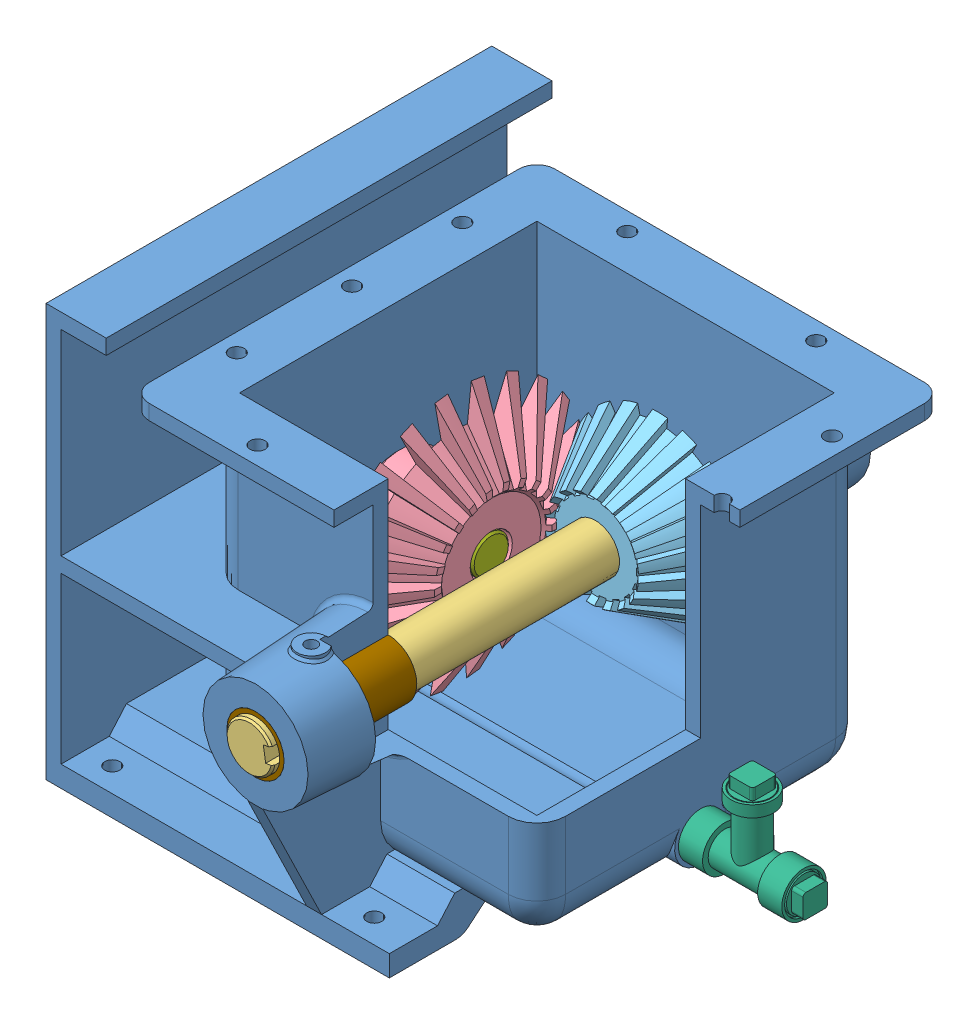
SolidWorks assembly Redutor do transportador helicoidal, configuration B. Lengths in mm.
Overall size (765.56 434.98 610).
10 component instances, 10 part files, 19 mates.
Components (placement in the parent):
- carcaça-1: carcaça [Valor predeterminado] at (-51.6856 -43.3778 0) size (496.49 434.98 593.28)
- peça 2-1: peça 2 [Valor predeterminado] at (-51.6856 -43.3778 -226.6406) x (0.95826 -0.2859 0) z (0 0 1) size (60 60 140)
- Peça 7-1: Peça 7 [Valor predeterminado] at (-47.7521 -42.7392 -61.7219) x (0 0 -1) z (0.160256 -0.987076 0) size (610 50.8 50.8)
- Peça 9B-1: Peça 9B [Valor predeterminado] at (-198.7206 -43.3778 0) x (1 0 0) z (0 0.964545 0.263918) size (104.77 270 268.87)
- Peça 9A-1: Peça 9A [Valor predeterminado] at (-51.6856 -43.3778 -153.7656) x (0 0 1) z (-0.662671 -0.74891 0) size (96.04 182.18 182.88)
- peça 21-1: peça 21 [Valor predeterminado] at (102.9549 -187.4434 0) size (138.87 105.45 46.9)
- Peça 4-1: Peça 4 [Valor predeterminado] at (-334.8151 -40.7927 0) size (423.91 48 48)
- Peça 5-1: Peça 5 [Valor predeterminado] at (-271.2606 -43.3778 0) x (0 -0.069308 -0.997595) z (0 -0.997595 0.069308) size (58 126 58)
- peça 1-1: peça 1 [Valor predeterminado] at (-51.6856 -43.3778 226.6406) x (0.8644 -0.502804 0) z (0 0 1) size (60 60 140)
- tampa-1: tampa [Valor predeterminado] at (-51.6856 129.2628 0) x (1 0 0) z (0 1 0) size (427.83 427.83 10) (hidden)
Mates (geometry in assembly coordinates):
- Concêntrico1: concentric aligned: cylinder of carcaça-1 through (-51.6856 -43.3778 -132.382) axis (0 0 -1) radius 30.1625; cylinder of peça 2-1 through (-51.6856 -43.3778 -156.6406) axis (0 0 -1) radius 30
- Coincidente1: coincident aligned: plane of carcaça-1 through (-51.6856 -43.3778 -296.6406) normal (0 0 -1); plane of peça 2-1 through (-51.6856 -43.3778 -296.6406) normal (0 0 -1)
- Concêntrico2: concentric anti-aligned: cylinder of Peça 7-1 through (-51.6856 -43.3778 -306.7219) axis (0 0 -1) radius 19.05; cylinder of Peça 9A-1 through (-51.6856 -43.3778 52.596) axis (0 0 1) radius 20
- Distância1: distance = 1 mm anti-aligned: plane of Peça 7-1 through (-26.6139 -39.3073 -61.7219) normal (0 0 -1); plane of Peça 9A-1 through (-22.3415 -10.2148 -62.7219) normal (0 0 1)
- Concêntrico3: concentric aligned: cylinder of peça 2-1 through (-51.6856 -43.3778 -156.6406) axis (0 0 -1) radius 21; cylinder of Peça 7-1 through (-51.6856 -43.3778 -306.7219) axis (0 0 -1) radius 19.05
- Distância2: distance = 3 mm anti-aligned: plane of Peça 9A-1 through (-66.6639 -30.1244 -153.7656) normal (0 0 -1); plane of carcaça-1 through (120.9549 -216.0184 -156.7656) normal (0 0 1)
- Concêntrico4: concentric aligned: cylinder of carcaça-1 through (-132.8094 -43.3778 0) axis (-1 0 0) radius 30.1625; cylinder of Peça 9B-1 through (-198.7206 -43.3778 0) axis (-1 0 0) radius 22.225
- RackPinionMate1: rack pinion = 79.375 mm: cylinder of Peça 9B-1 through (-198.7206 -43.3778 0) axis (-1 0 0) radius 49.2125; cylinder of Peça 9A-1 through (-51.6856 -43.3778 52.596) axis (0 0 1) radius 39.6875
- Concêntrico5: concentric aligned: cylinder of carcaça-1 through (-179.5025 -187.4434 0) axis (1 0 0) radius 13.8906; cylinder of peça 21-1 through (229.828 -187.4434 0) axis (1 0 0) radius 13.5
- Coincidente5: coincident anti-aligned: plane of carcaça-1 through (120.9549 129.2628 172.6406) normal (1 0 0); plane of peça 21-1 through (120.9549 -173.9434 0) normal (-1 0 0)
- Concêntrico7: concentric anti-aligned: cylinder of Peça 9B-1 through (-198.7206 -43.3778 0) axis (-1 0 0) radius 22.225; cylinder of Peça 4-1 through (-99.8151 -43.3778 0) axis (1 0 0) radius 20
- Coincidente7: coincident aligned: plane of Peça 9B-1 through (-99.8151 -29.5354 -50.5902) normal (1 0 0); plane of Peça 4-1 through (-99.8151 -23.3778 0) normal (1 0 0)
- Concêntrico8: concentric anti-aligned: cylinder of Peça 4-1 through (-99.8151 -43.3778 0) axis (1 0 0) radius 20; cylinder of Peça 5-1 through (-208.2606 -43.3778 0) axis (-1 0 0) radius 21
- Coincidente8: coincident aligned: plane of carcaça-1 through (-334.2606 -227.7684 164.9301) normal (-1 0 0); plane of Peça 5-1 through (-334.2606 -43.3778 0) normal (-1 0 0)
- Concêntrico9: concentric aligned: cylinder of Peça 7-1 through (-51.6856 -43.3778 -306.7219) axis (0 0 -1) radius 25.4; cylinder of peça 1-1 through (-51.6856 -43.3778 296.6406) axis (0 0 -1) radius 25.5
- Coincidente9: coincident aligned: plane of carcaça-1 through (-51.6856 -43.3778 296.6406) normal (0 0 1); plane of peça 1-1 through (-51.6856 -43.3778 296.6406) normal (0 0 1)
- Coincidente10: coincident anti-aligned: plane of carcaça-1 through (120.9549 129.2628 -172.6406) normal (0 1 0); plane of tampa-1 through (143.18 129.2628 194.8656) normal (0 -1 0)
- Concêntrico10: concentric anti-aligned: cylinder of carcaça-1 through (-151.3013 113.3878 194.8656) axis (0 1 0) radius 7.9375; cylinder of tampa-1 through (-151.3013 139.2628 194.8656) axis (0 -1 0) radius 7.9375
- Concêntrico11: concentric anti-aligned: cylinder of carcaça-1 through (47.93 113.3878 194.8656) axis (0 1 0) radius 7.9375; cylinder of tampa-1 through (47.93 139.2628 194.8656) axis (0 -1 0) radius 7.9375
